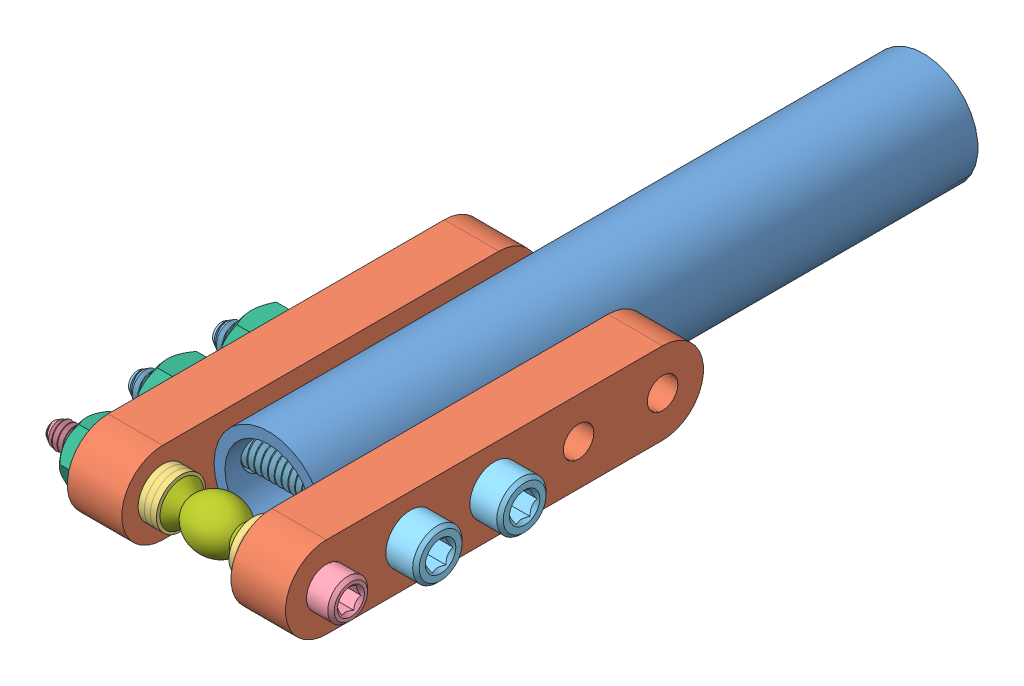
SolidWorks assembly Diff Pivot Bottom, configuration Default. Lengths in mm.
Overall size (35.29 12.7 86.93).
16 component instances, 7 part files, 32 mates.
Components (placement in the parent):
- 3 inch Aluminum Rod-1: 3 inch Aluminum Rod [Default] at (25.2275 39.993 -257.4677) size (12.7 12.7 76.2)
- 5 Hole Aluminum Beam-1: 5 Hole Aluminum Beam [Default] at (37.9275 39.993 84.5433) x (0 0 -1) z (0 1 0) size (48.64 6.35 9.53)
- 5 Hole Aluminum Beam-2: 5 Hole Aluminum Beam [Default] at (18.8775 39.993 84.5433) x (0 0 -1) z (0 1 0) size (48.64 6.35 9.53)
- 4-40 Washer-1: 4-40 Washer [Default] at (18.8775 39.993 104.1013) x (0 -1 0) z (0 0 1) size (5.71 0.71 5.71)
- 4-40 Washer-2: 4-40 Washer [Default] at (19.5887 39.993 104.1013) x (0 -1 0) z (0 0 1) size (5.71 0.71 5.71)
- 4-40 Washer-3: 4-40 Washer [Default] at (20.2999 39.993 104.1013) x (0 -1 0) z (0 0 1) size (5.71 0.71 5.71)
- 4-40 Washer-4: 4-40 Washer [Default] at (29.4439 39.993 104.1013) x (0 -1 0) z (0 0 1) size (5.71 0.71 5.71)
- 4-40 Washer-5: 4-40 Washer [Default] at (30.1551 39.993 104.1013) x (0 -1 0) z (0 0 1) size (5.71 0.71 5.71)
- 4-40 Washer-6: 4-40 Washer [Default] at (30.8663 39.993 104.1013) x (0 -1 0) z (0 0 1) size (5.71 0.71 5.71)
- 4-40_SHCS-1: 4-40_SHCS [4-40 SHCS X 1.250] at (6.1775 39.993 104.1013) x (0 0.924225 0.381849) z (1 0 0) size (4.65 4.65 34.63)
- 6-32_SHCS-1: 6-32_SHCS [6-32 SHCS X 1.250] at (6.1775 39.993 94.3223) x (0 0 -1) z (1 0 0) size (5.74 5.74 35.26)
- 6-32_SHCS-2: 6-32_SHCS [6-32 SHCS X 1.250] at (6.1775 39.993 84.5433) x (0 0 -1) z (1 0 0) size (5.74 5.74 35.26)
- hex_nut-2: hex_nut [#4-40] at (12.5275 39.993 104.1013) x (0 0.381849 -0.924225) z (0 0.924225 0.381849) size (6.35 2.49 8.06)
- hex_nut-3: hex_nut [#6-32] at (12.5275 39.993 94.3223) x (0 0.381849 -0.924225) z (0 0.924225 0.381849) size (7.92 2.9 10.06)
- hex_nut-4: hex_nut [#6-32] at (12.5275 39.993 84.5433) x (0 1 0) z (0 0 1) size (7.92 2.9 10.06)
- Ball bearing-1: Ball bearing [Default] at (21.1 39.993 104.1013) x (0 -1 0) z (0 0 1) size (5.73 8.26 5.73)
Mates (geometry in assembly coordinates):
- Concentric1: concentric anti-aligned: cylinder of 3 inch Aluminum Rod-1 through (-152.5725 39.993 84.5433) axis (1 0 0) radius 1.9558; cylinder of 5 Hole Aluminum Beam-2 through (12.5275 39.993 84.5433) axis (-1 0 0) radius 1.778
- Concentric2: concentric anti-aligned: cylinder of 3 inch Aluminum Rod-1 through (-152.5725 39.993 84.5433) axis (1 0 0) radius 1.9558; cylinder of 5 Hole Aluminum Beam-1 through (31.5775 39.993 84.5433) axis (-1 0 0) radius 1.778
- Concentric3: concentric aligned: cylinder of 5 Hole Aluminum Beam-2 through (12.5275 39.993 94.3223) axis (-1 0 0) radius 1.778; cylinder of 5 Hole Aluminum Beam-1 through (31.5775 39.993 94.3223) axis (-1 0 0) radius 1.778
- Concentric4: concentric anti-aligned: cylinder of 5 Hole Aluminum Beam-2 through (12.5275 39.993 94.3223) axis (-1 0 0) radius 1.778; cylinder of 3 inch Aluminum Rod-1 through (-152.5725 39.993 94.3223) axis (1 0 0) radius 1.9558
- Concentric5: concentric anti-aligned: cylinder of 3 inch Aluminum Rod-1 through (-152.5725 39.993 84.5433) axis (1 0 0) radius 1.9558; cylinder of hex_nut-4 through (12.4514 39.993 84.5433) axis (-1 0 0) radius 1.323
- Concentric7: concentric anti-aligned: cylinder of 3 inch Aluminum Rod-1 through (-152.5725 39.993 84.5433) axis (1 0 0) radius 1.9558; cylinder of 6-32_SHCS-2 through (50.6275 39.993 84.5433) axis (-1 0 0) radius 2.8702
- Concentric8: concentric anti-aligned: cylinder of 6-32_SHCS-1 through (50.6275 39.993 94.3223) axis (-1 0 0) radius 2.8702; cylinder of 3 inch Aluminum Rod-1 through (-152.5725 39.993 94.3223) axis (1 0 0) radius 1.9558
- Concentric9: concentric aligned: cylinder of 6-32_SHCS-1 through (50.6275 39.993 94.3223) axis (-1 0 0) radius 2.8702; cylinder of hex_nut-3 through (12.4514 39.993 94.3223) axis (-1 0 0) radius 1.323
- Concentric10: concentric anti-aligned: cylinder of 5 Hole Aluminum Beam-1 through (31.5775 39.993 104.1013) axis (-1 0 0) radius 1.778; cylinder of 4-40 Washer-5 through (30.8663 39.993 104.1013) axis (1 0 0) radius 1.4732
- Concentric11: concentric anti-aligned: cylinder of 5 Hole Aluminum Beam-1 through (31.5775 39.993 104.1013) axis (-1 0 0) radius 1.778; cylinder of 4-40 Washer-6 through (31.5775 39.993 104.1013) axis (1 0 0) radius 1.4732
- Concentric12: concentric anti-aligned: cylinder of 5 Hole Aluminum Beam-1 through (31.5775 39.993 104.1013) axis (-1 0 0) radius 1.778; cylinder of 4-40 Washer-4 through (30.1551 39.993 104.1013) axis (1 0 0) radius 1.4732
- Concentric13: concentric anti-aligned: cylinder of 5 Hole Aluminum Beam-1 through (31.5775 39.993 104.1013) axis (-1 0 0) radius 1.778; cylinder of 4-40 Washer-3 through (21.0111 39.993 104.1013) axis (1 0 0) radius 1.4732
- Concentric14: concentric anti-aligned: cylinder of 5 Hole Aluminum Beam-1 through (31.5775 39.993 104.1013) axis (-1 0 0) radius 1.778; cylinder of 4-40 Washer-2 through (20.2999 39.993 104.1013) axis (1 0 0) radius 1.4732
- Concentric15: concentric anti-aligned: cylinder of 5 Hole Aluminum Beam-1 through (31.5775 39.993 104.1013) axis (-1 0 0) radius 1.778; cylinder of 4-40 Washer-1 through (19.5887 39.993 104.1013) axis (1 0 0) radius 1.4732
- Concentric16: concentric aligned: cylinder of 5 Hole Aluminum Beam-1 through (31.5775 39.993 104.1013) axis (-1 0 0) radius 1.778; cylinder of 4-40_SHCS-1 through (50.6275 39.993 104.1013) axis (-1 0 0) radius 2.3241
- Concentric17: concentric aligned: cylinder of 5 Hole Aluminum Beam-1 through (31.5775 39.993 104.1013) axis (-1 0 0) radius 1.778; cylinder of hex_nut-2 through (12.1339 39.993 104.1013) axis (-1 0 0) radius 1.0787
- Tangent1: tangent anti-aligned: cylinder of 3 inch Aluminum Rod-1 through (25.2275 39.993 98.1323) axis (0 0 -1) radius 6.35; plane of 5 Hole Aluminum Beam-1 through (31.5775 39.993 104.1013) normal (-1 0 0)
- Tangent2: tangent anti-aligned: cylinder of 3 inch Aluminum Rod-1 through (25.2275 39.993 98.1323) axis (0 0 -1) radius 6.35; plane of 5 Hole Aluminum Beam-2 through (18.8775 39.993 104.1013) normal (1 0 0)
- Coincident1: coincident anti-aligned: plane of 5 Hole Aluminum Beam-1 through (37.9275 39.993 104.1013) normal (1 0 0); plane of 6-32_SHCS-1 through (37.9275 39.993 94.3223) normal (-1 0 0)
- Coincident2: coincident anti-aligned: plane of 5 Hole Aluminum Beam-1 through (37.9275 39.993 104.1013) normal (1 0 0); plane of 6-32_SHCS-2 through (37.9275 39.993 84.5433) normal (-1 0 0)
- Coincident3: coincident anti-aligned: plane of 5 Hole Aluminum Beam-1 through (37.9275 39.993 104.1013) normal (1 0 0); plane of 4-40_SHCS-1 through (37.9275 39.993 104.1013) normal (-1 0 0)
- Coincident4: coincident anti-aligned: plane of 5 Hole Aluminum Beam-2 through (12.5275 39.993 104.1013) normal (-1 0 0); plane of hex_nut-3 through (12.5275 32.137 95.3638) normal (1 0 0)
- Coincident5: coincident anti-aligned: plane of 5 Hole Aluminum Beam-2 through (12.5275 39.993 104.1013) normal (-1 0 0); plane of hex_nut-2 through (12.5275 36.6047 102.7014) normal (1 0 0)
- Coincident6: coincident anti-aligned: plane of 5 Hole Aluminum Beam-2 through (12.5275 39.993 104.1013) normal (-1 0 0); plane of hex_nut-4 through (12.5275 36.0306 77.6803) normal (1 0 0)
- Coincident7: coincident anti-aligned: plane of 4-40 Washer-5 through (30.8663 39.993 104.1013) normal (1 0 0); plane of 4-40 Washer-6 through (30.8663 39.993 104.1013) normal (-1 0 0)
- Coincident8: coincident anti-aligned: plane of 4-40 Washer-4 through (30.1551 39.993 104.1013) normal (1 0 0); plane of 4-40 Washer-5 through (30.1551 39.993 104.1013) normal (-1 0 0)
- Coincident9: coincident anti-aligned: plane of 4-40 Washer-2 through (20.2999 39.993 104.1013) normal (1 0 0); plane of 4-40 Washer-3 through (20.2999 39.993 104.1013) normal (-1 0 0)
- Coincident10: coincident anti-aligned: plane of 4-40 Washer-1 through (19.5887 39.993 104.1013) normal (1 0 0); plane of 4-40 Washer-2 through (19.5887 39.993 104.1013) normal (-1 0 0)
- Coincident11: coincident anti-aligned: plane of 5 Hole Aluminum Beam-1 through (31.5775 39.993 104.1013) normal (-1 0 0); plane of 4-40 Washer-6 through (31.5775 39.993 104.1013) normal (1 0 0)
- Coincident12: coincident anti-aligned: plane of 5 Hole Aluminum Beam-2 through (18.8775 39.993 104.1013) normal (1 0 0); plane of 4-40 Washer-1 through (18.8775 39.993 104.1013) normal (-1 0 0)
- Coincident13: coincident anti-aligned: plane of Ball bearing-1 through (25.2275 39.993 104.1013) normal (1 0 0)
- Concentric18: concentric anti-aligned: cylinder of 4-40_SHCS-1 through (50.6275 39.993 104.1013) axis (-1 0 0) radius 2.3241; cylinder of Ball bearing-1 through (29.101 39.993 104.1013) axis (1 0 0) radius 1.016
